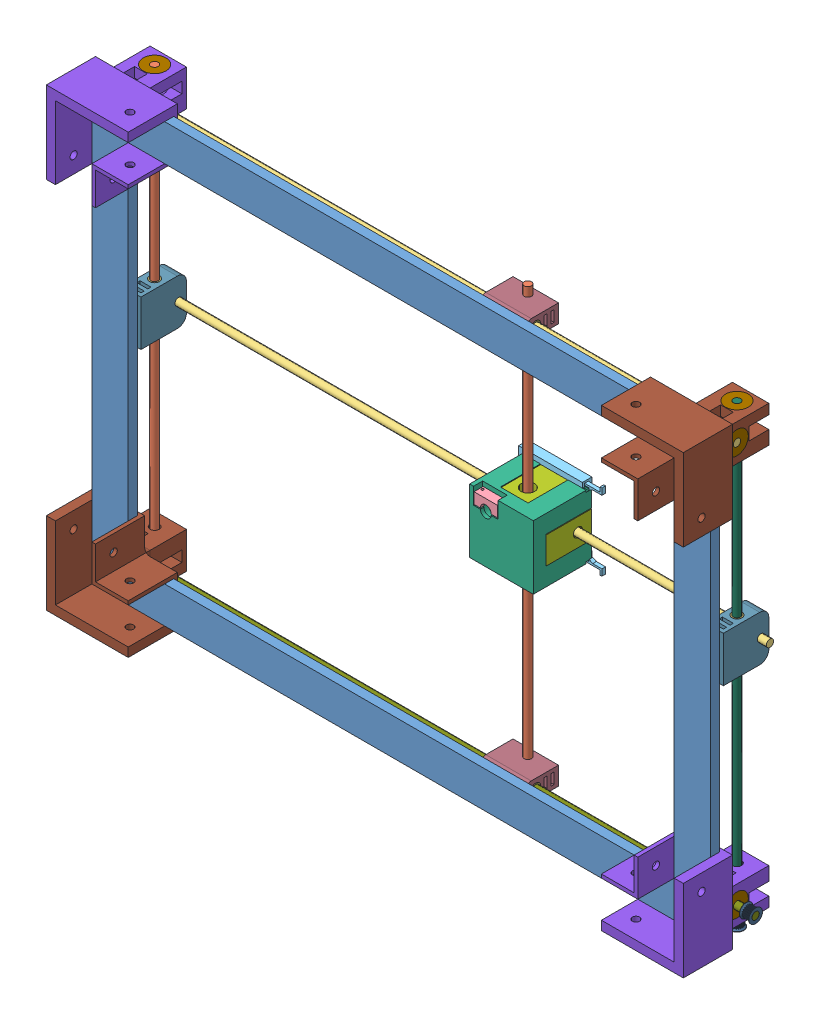
SolidWorks assembly Assemblage_XY, configuration Défaut. Lengths in mm.
Overall size (711.84 510.5 125.29).
50 component instances, 16 part files, 70 mates.
Components (placement in the parent):
- Cadre_XY-1: Cadre_XY [Défaut] at (379.0068 -247.2078 675) size (680 480 10)
- AXE_8X480-2: AXE_8X480 [Défaut] at (-280.9932 -247.2078 636) x (0.987721 0 0.156231) z (0 1 0) size (8 8 480)
- AXE_8X680-1: AXE_8X680 [Défaut] at (379.0068 212.7922 656) x (0 0.013067 0.999915) z (-1 0 0) size (8 8 680)
- AXE_8X480-3: AXE_8X480 [Défaut] at (132.8746 232.7922 639.7) x (0.999527 0 0.030742) z (0 -1 0) size (8 8 480)
- AXE_8X680-3: AXE_8X680 [Défaut] at (-300.9932 3.8544 619.7) x (0 -0.696158 -0.717888) z (1 0 0) size (8 8 680)
- P3DMIPC-Tête_complete-1: P3DMIPC-Tête_complete [Défaut] at (88.682 17.2244 635.2981) x (0 1 0) z (1 0 0) size (84 69 89)
  - P3DMIPC-Clip_Buse_E3D-1: P3DMIPC-Clip_Buse_E3D [Défaut] at (17.0518 23.4109 40.0035) x (1 0 0) z (0 1 0) size (12 26 10)
  - P3DMIPC-Clip_tête-1: P3DMIPC-Clip_tête [Défaut] at (26.9018 -25.0891 4.5597) x (1 0 0) z (0 -1 0) size (84 89 10.5)
  - P3DMIPC-Porte_Buse_E3DX1-1: P3DMIPC-Porte_Buse_E3DX1 [Défaut] at (22.03 33.4019 79.1927) x (0 0 1) z (0 -1 0) size (70 70 64)
  - P3DMIPC-Chariot-1: P3DMIPC-Chariot [Défaut] at (-48.37 -30.5981 79.1927) size (70 50 70)
- Angle_magique_G-1: Angle_magique_G [Défaut] at (379.0068 -247.2078 675) x (-1 0 0) z (0 0 -1) size (91.34 90 104)
- F608ZZ-1: F608ZZ [Défaut] at (372.0068 -227.2078 656) x (0 -0.924225 -0.381849) z (1 0 0) size (25 25 7)
- Angle_magique_G-4: Angle_magique_G [Défaut] at (-300.9932 232.7922 675) x (1 0 0) z (0 0 -1) size (91.34 90 104)
- pulley_gt2_3mm_20t-10: pulley_gt2_3mm_20t [Défaut] at (-280.9932 209.5422 636) x (0.106795 0 0.994281) z (0 1 0) size (15 15 10.5)
- pulley_gt2_3mm_20t-11: pulley_gt2_3mm_20t [Défaut] at (-277.7432 212.7922 656) x (0 0.106795 0.994281) z (-1 0 0) size (15 15 10.5)
- pulley_gt2_3mm_20t-12: pulley_gt2_3mm_20t [Défaut] at (-280.9932 -236.4578 636) x (-0.771074 0 0.636745) z (0 1 0) size (15 15 10.5)
- pulley_gt2_3mm_20t-13: pulley_gt2_3mm_20t [Défaut] at (-277.7432 -227.2078 656) x (0 0.106795 0.994281) z (-1 0 0) size (15 15 10.5)
- pulley_gt2_3mm_20t-15: pulley_gt2_3mm_20t [Défaut] at (359.0068 222.0422 636) x (-0.106795 0 0.994281) z (0 -1 0) size (15 15 10.5)
- pulley_gt2_3mm_20t-16: pulley_gt2_3mm_20t [Défaut] at (368.2568 212.7922 656) x (0 0.106795 0.994281) z (-1 0 0) size (15 15 10.5)
- F608ZZ-2: F608ZZ [Défaut] at (-280.9932 225.7922 636) x (-0.546944 0 0.837169) z (0 1 0) size (25 25 7)
- F608ZZ-3: F608ZZ [Défaut] at (-293.9932 212.7922 656) x (0 0 1) z (-1 0 0) size (25 25 7)
- F608ZZ-4: F608ZZ [Défaut] at (-293.9932 -227.2078 656) x (0 0 1) z (-1 0 0) size (25 25 7)
- F608ZZ-5: F608ZZ [Défaut] at (-280.9932 -240.2078 636) x (-0.924225 0 -0.381849) z (0 -1 0) size (25 25 7)
- F608ZZ-6: F608ZZ [Défaut] at (359.0068 -240.2078 636) x (-0.546944 0 0.837169) z (0 -1 0) size (25 25 7)
- F608ZZ-7: F608ZZ [Défaut] at (372.0068 212.7922 656) x (0 0 1) z (1 0 0) size (25 25 7)
- F608ZZ-8: F608ZZ [Défaut] at (359.0068 225.7922 636) x (0 0 1) z (0 1 0) size (25 25 7)
- Angle_magique_D-1: Angle_magique_D [Défaut] at (-300.9932 -247.2078 675) x (0 1 0) z (0 0 -1) size (90 91.34 104)
- Angle_magique_D-2: Angle_magique_D [Défaut] at (379.0068 232.7922 675) x (0 -1 0) z (0 0 -1) size (90 91.34 104)
- Assemblage_glissière_block_belt_palier_AR-1: Assemblage_glissière_block_belt_palier_AR [Défaut] at (253.3996 -186.4667 609.4689) x (0 -1 0) z (-1 0 0) size (20 35 50)
  - ultimaker_cuivre_fritté_douille_8mmx11mmx22 mm-1: ultimaker_cuivre_fritté_douille_8mmx11mmx22 mm [Défaut] at (40.7411 46.5311 95.5249) size (11 11 22)
  - ultimaker_cuivre_fritté_douille_8mmx11mmx22 mm-2: ultimaker_cuivre_fritté_douille_8mmx11mmx22 mm [Défaut] at (40.7411 46.5311 123.5249) size (11 11 22)
  - Glisière_block_belt_AR-2: Glisière_block_belt_AR [Défaut] at (50.7411 14.5311 95.5249) size (20 35 50)
- Assemblage_glissière_block_belt_palier_AR-2: Assemblage_glissière_block_belt_palier_AR [Défaut] at (12.3497 172.0511 609.4689) x (0 1 0) z (1 0 0) size (20 35 50)
  - ultimaker_cuivre_fritté_douille_8mmx11mmx22 mm-1: ultimaker_cuivre_fritté_douille_8mmx11mmx22 mm [Défaut] at (40.7411 46.5311 95.5249) size (11 11 22)
  - ultimaker_cuivre_fritté_douille_8mmx11mmx22 mm-2: ultimaker_cuivre_fritté_douille_8mmx11mmx22 mm [Défaut] at (40.7411 46.5311 123.5249) size (11 11 22)
  - Glisière_block_belt_AR-2: Glisière_block_belt_AR [Défaut] at (50.7411 14.5311 95.5249) size (20 35 50)
- pulley_gt2_3mm_20t-17: pulley_gt2_3mm_20t [Défaut] at (368.2568 -227.2078 656) x (0 0.106795 0.994281) z (-1 0 0) size (15 15 10.5)
- pulley_gt2_3mm_20t-18: pulley_gt2_3mm_20t [Défaut] at (359.0068 -223.9578 636) x (0.203502 0 0.979074) z (0 -1 0) size (15 15 10.5)
- Assemblage_glissière_block_belt_palier_GD-1: Assemblage_glissière_block_belt_palier_GD [Défaut] at (364.4936 -71.1456 631.6132) x (-1 0 0) z (0 1 0) size (20 50 50)
  - Glisière_block_belt_GD-1: Glisière_block_belt_GD [Défaut] at (15.4869 -20.6132 50) size (20 50 50)
  - ultimaker_cuivre_fritté_douille_8mmx11mmx22 mm-1: ultimaker_cuivre_fritté_douille_8mmx11mmx22 mm [Défaut] at (5.4869 4.3868 50) size (11 11 22)
  - ultimaker_cuivre_fritté_douille_8mmx11mmx22 mm-2: ultimaker_cuivre_fritté_douille_8mmx11mmx22 mm [Défaut] at (5.4869 4.3868 78) size (11 11 22)
- Assemblage_glissière_block_belt_palier_GD-2: Assemblage_glissière_block_belt_palier_GD [Défaut] at (-286.4801 78.8544 631.6132) x (1 0 0) z (0 -1 0) size (20 50 50)
  - Glisière_block_belt_GD-1: Glisière_block_belt_GD [Défaut] at (15.4869 -20.6132 50) size (20 50 50)
  - ultimaker_cuivre_fritté_douille_8mmx11mmx22 mm-1: ultimaker_cuivre_fritté_douille_8mmx11mmx22 mm [Défaut] at (5.4869 4.3868 50) size (11 11 22)
  - ultimaker_cuivre_fritté_douille_8mmx11mmx22 mm-2: ultimaker_cuivre_fritté_douille_8mmx11mmx22 mm [Défaut] at (5.4869 4.3868 78) size (11 11 22)
- AXE_8X500_Moteur-1: AXE_8X500_Moteur [Défaut] at (359.0068 -267.7078 636) x (0.283264 0 -0.959042) z (0 1 0) size (8 8 500.5)
- AXE_8X700_Moteur-1: AXE_8X700_Moteur [Défaut] at (399.5068 -227.2078 656) x (0 0 1) z (-1 0 0) size (8 8 700.5)
- pulley_gt2_3mm_20t-19: pulley_gt2_3mm_20t [Défaut] at (359.0068 -256.2078 636) x (0.203502 0 0.979074) z (0 -1 0) size (15 15 10.5)
- pulley_gt2_3mm_20t-20: pulley_gt2_3mm_20t [Défaut] at (388.0068 -227.2078 656) x (0 0.203502 0.979074) z (1 0 0) size (15 15 10.5)
Mates (geometry in assembly coordinates):
- Coaxiale1: concentric anti-aligned: cylinder of AXE_8X680-3 through (379.0068 3.8544 619.7) axis (-1 0 0) radius 4; cylinder of P3DMIPC-Tête_complete-1/P3DMIPC-Chariot-1 through (163.8746 3.8544 619.7) axis (1 0 0) radius 5
- Coaxiale2: concentric anti-aligned: cylinder of AXE_8X480-3 through (132.8746 -247.2078 639.7) axis (0 1 0) radius 4; cylinder of P3DMIPC-Tête_complete-1/P3DMIPC-Chariot-1 through (132.8746 -27.1456 639.7) axis (0 -1 0) radius 5
- Coïncidente14: coincident anti-aligned: plane of Cadre_XY-1 through (379.0068 -247.2078 675) normal (0 0 -1); plane of Angle_magique_G-1 through (379.0068 -247.2078 675) normal (0 0 1)
- Coïncidente15: coincident anti-aligned: plane of Cadre_XY-1 through (379.0068 -247.2078 685) normal (1 0 0); plane of Angle_magique_G-1 through (379.0068 -247.2078 725) normal (-1 0 0)
- Coïncidente16: coincident anti-aligned: plane of Cadre_XY-1 through (379.0068 -247.2078 685) normal (0 -1 0); plane of Angle_magique_G-1 through (299.0068 -247.2078 725) normal (0 1 0)
- Coïncidente27: coincident anti-aligned: plane of Cadre_XY-1 through (379.0068 -247.2078 675) normal (0 0 -1); plane of Angle_magique_G-4 through (-300.9932 232.7922 675) normal (0 0 1)
- Coïncidente28: coincident anti-aligned: plane of Cadre_XY-1 through (379.0068 232.7922 685) normal (0 1 0); plane of Angle_magique_G-4 through (-220.9932 232.7922 725) normal (0 -1 0)
- Coïncidente29: coincident anti-aligned: plane of Cadre_XY-1 through (-300.9932 -247.2078 685) normal (-1 0 0); plane of Angle_magique_G-4 through (-300.9932 232.7922 725) normal (1 0 0)
- Coaxiale17: concentric anti-aligned: cylinder of AXE_8X680-1 through (-300.9932 212.7922 656) axis (1 0 0) radius 4; cylinder of pulley_gt2_3mm_20t-11 through (-277.7432 212.7922 656) axis (-1 0 0) radius 4
- Coaxiale18: concentric aligned: cylinder of AXE_8X680-1 through (-300.9932 212.7922 656) axis (1 0 0) radius 4; cylinder of Angle_magique_G-4 through (-310.9932 212.7922 656) axis (1 0 0) radius 5
- Coïncidente30: coincident aligned: plane of Cadre_XY-1 through (-300.9932 -247.2078 685) normal (-1 0 0); plane of AXE_8X680-1 through (-300.9932 212.7922 656) normal (-1 0 0)
- Distance2: distance = 2.75 mm anti-aligned: plane of pulley_gt2_3mm_20t-11 through (-278.7432 212.7922 656) normal (1 0 0); plane of Angle_magique_G-4 through (-275.9932 192.7922 621) normal (-1 0 0)
- Coaxiale19: concentric anti-aligned: cylinder of AXE_8X680-1 through (-300.9932 212.7922 656) axis (1 0 0) radius 4; cylinder of pulley_gt2_3mm_20t-16 through (368.2568 212.7922 656) axis (-1 0 0) radius 4
- Coaxiale24: concentric aligned: cylinder of AXE_8X480-2 through (-280.9932 232.7922 636) axis (0 -1 0) radius 4; cylinder of Angle_magique_G-4 through (-280.9932 232.7923 636) axis (0 -1 0) radius 5
- Coaxiale25: concentric anti-aligned: cylinder of AXE_8X480-2 through (-280.9932 232.7922 636) axis (0 -1 0) radius 4; cylinder of pulley_gt2_3mm_20t-10 through (-280.9932 209.5422 636) axis (0 1 0) radius 4
- Coïncidente34: coincident aligned: plane of Cadre_XY-1 through (379.0068 232.7922 685) normal (0 1 0); plane of AXE_8X480-2 through (-280.9932 232.7922 636) normal (0 1 0)
- Distance4: distance = 2.75 mm anti-aligned: plane of pulley_gt2_3mm_20t-10 through (-280.9932 210.5422 636) normal (0 -1 0); plane of Angle_magique_G-4 through (-275.9932 207.7922 621) normal (0 1 0)
- Coaxiale26: concentric anti-aligned: cylinder of AXE_8X480-2 through (-280.9932 232.7922 636) axis (0 -1 0) radius 4; cylinder of pulley_gt2_3mm_20t-12 through (-280.9932 -236.4578 636) axis (0 1 0) radius 4
- Coïncidente44: coincident anti-aligned: plane of Cadre_XY-1 through (379.0068 -247.2078 675) normal (0 0 -1); plane of Angle_magique_D-1 through (-300.9932 -247.2078 675) normal (0 0 1)
- Coïncidente45: coincident anti-aligned: plane of Cadre_XY-1 through (379.0068 -247.2078 685) normal (0 -1 0); plane of Angle_magique_D-1 through (-300.9932 -247.2078 725) normal (0 1 0)
- Coïncidente46: coincident anti-aligned: plane of Cadre_XY-1 through (-300.9932 -247.2078 685) normal (-1 0 0); plane of Angle_magique_D-1 through (-300.9932 -167.2078 725) normal (1 0 0)
- Distance10: distance = 2.75 mm anti-aligned: plane of Angle_magique_D-1 through (-260.9932 -222.2078 621) normal (0 -1 0); plane of pulley_gt2_3mm_20t-12 through (-280.9932 -224.9578 636) normal (0 1 0)
- Coïncidente51: coincident anti-aligned: plane of Cadre_XY-1 through (379.0068 -247.2078 675) normal (0 0 -1); plane of Angle_magique_D-2 through (379.0068 232.7922 675) normal (0 0 1)
- Coïncidente52: coincident anti-aligned: plane of Cadre_XY-1 through (379.0068 232.7922 685) normal (0 1 0); plane of Angle_magique_D-2 through (379.0068 232.7922 725) normal (0 -1 0)
- Coïncidente53: coincident anti-aligned: plane of Cadre_XY-1 through (379.0068 -247.2078 685) normal (1 0 0); plane of Angle_magique_D-2 through (379.0068 152.7922 725) normal (-1 0 0)
- Distance11: distance = 2.75 mm anti-aligned: plane of pulley_gt2_3mm_20t-15 through (359.0068 210.5422 636) normal (0 -1 0); plane of Angle_magique_D-2 through (339.0068 207.7922 621) normal (0 1 0)
- Distance12: distance = 2.75 mm anti-aligned: plane of Angle_magique_D-2 through (354.0068 207.7922 621) normal (1 0 0); plane of pulley_gt2_3mm_20t-16 through (356.7568 212.7922 656) normal (-1 0 0)
- Coaxiale39: concentric anti-aligned: cylinder of AXE_8X680-1 through (-300.9932 212.7922 656) axis (1 0 0) radius 4; cylinder of Assemblage_glissière_block_belt_palier_AR-2/ultimaker_cuivre_fritté_douille_8mmx11mmx22 mm-1 through (129.8746 212.7922 656) axis (-1 0 0) radius 4
- Coaxiale42: concentric anti-aligned: cylinder of AXE_8X480-3 through (132.8746 -247.2078 639.7) axis (0 1 0) radius 4; cylinder of Assemblage_glissière_block_belt_palier_AR-2/Glisière_block_belt_AR-2 through (132.8746 222.7922 639.7) axis (0 -1 0) radius 4
- Coaxiale43: concentric aligned: cylinder of AXE_8X480-3 through (132.8746 -247.2078 639.7) axis (0 1 0) radius 4; cylinder of Assemblage_glissière_block_belt_palier_AR-1/Glisière_block_belt_AR-2 through (132.8746 -237.2078 639.7) axis (0 1 0) radius 4
- Coaxiale50: concentric anti-aligned: cylinder of F608ZZ-7 through (377.5068 212.7922 656) axis (-1 0 0) radius 11; cylinder of Angle_magique_D-2 through (372.0068 212.7922 656) axis (1 0 0) radius 11
- Coïncidente63: coincident anti-aligned: plane of F608ZZ-7 through (372.0068 212.7922 656) normal (-1 0 0); plane of Angle_magique_D-2 through (372.0068 212.7922 656) normal (1 0 0)
- Coaxiale51: concentric anti-aligned: cylinder of F608ZZ-8 through (359.0068 231.2922 636) axis (0 -1 0) radius 11; cylinder of Angle_magique_D-2 through (359.0068 225.7922 636) axis (0 1 0) radius 11
- Coïncidente64: coincident anti-aligned: plane of F608ZZ-8 through (359.0068 225.7922 636) normal (0 -1 0); plane of Angle_magique_D-2 through (359.0068 225.7922 636) normal (0 1 0)
- Coïncidente65: coincident anti-aligned: plane of Angle_magique_G-4 through (-280.9932 225.7922 636) normal (0 1 0); plane of F608ZZ-2 through (-280.9932 225.7922 636) normal (0 -1 0)
- Coaxiale53: concentric anti-aligned: cylinder of Angle_magique_G-4 through (-280.9932 225.7922 636) axis (0 1 0) radius 11; cylinder of F608ZZ-2 through (-280.9932 231.2922 636) axis (0 -1 0) radius 11
- Coaxiale54: concentric anti-aligned: cylinder of Angle_magique_G-4 through (-293.9932 212.7922 656) axis (-1 0 0) radius 11; cylinder of F608ZZ-3 through (-299.4932 212.7922 656) axis (1 0 0) radius 11
- Coïncidente66: coincident anti-aligned: plane of Angle_magique_G-4 through (-293.9932 212.7922 656) normal (-1 0 0); plane of F608ZZ-3 through (-293.9932 212.7922 656) normal (1 0 0)
- Coaxiale57: concentric anti-aligned: cylinder of F608ZZ-4 through (-299.4932 -227.2078 656) axis (1 0 0) radius 11; cylinder of Angle_magique_D-1 through (-293.9932 -227.2078 656) axis (-1 0 0) radius 11
- Coïncidente69: coincident anti-aligned: plane of F608ZZ-4 through (-293.9932 -227.2078 656) normal (1 0 0); plane of Angle_magique_D-1 through (-293.9932 -227.2078 656) normal (-1 0 0)
- Coïncidente70: coincident anti-aligned: plane of F608ZZ-5 through (-280.9932 -240.2078 636) normal (0 1 0); plane of Angle_magique_D-1 through (-280.9932 -240.2078 636) normal (0 -1 0)
- Coaxiale58: concentric anti-aligned: cylinder of F608ZZ-5 through (-280.9932 -245.7078 636) axis (0 1 0) radius 11; cylinder of Angle_magique_D-1 through (-280.9932 -240.2078 636) axis (0 -1 0) radius 11
- Distance14: distance = 2.75 mm anti-aligned: plane of Angle_magique_G-1 through (354.0068 -222.2078 621) normal (0 -1 0); plane of pulley_gt2_3mm_20t-18 through (359.0068 -224.9578 636) normal (0 1 0)
- Distance15: distance = 2.75 mm anti-aligned: plane of Angle_magique_G-1 through (354.0068 -207.2078 621) normal (1 0 0); plane of pulley_gt2_3mm_20t-17 through (356.7568 -227.2078 656) normal (-1 0 0)
- Coïncidente73: coincident anti-aligned: plane of Angle_magique_G-1 through (359.0068 -240.2078 636) normal (0 -1 0); plane of F608ZZ-6 through (359.0068 -240.2078 636) normal (0 1 0)
- Coaxiale61: concentric anti-aligned: cylinder of Angle_magique_G-1 through (359.0068 -240.2078 636) axis (0 -1 0) radius 11; cylinder of F608ZZ-6 through (359.0068 -245.7078 636) axis (0 1 0) radius 11
- Coïncidente74: coincident anti-aligned: plane of Angle_magique_G-1 through (372.0068 -227.2078 656) normal (1 0 0); plane of F608ZZ-1 through (372.0068 -227.2078 656) normal (-1 0 0)
- Coaxiale62: concentric anti-aligned: cylinder of Angle_magique_G-1 through (372.0068 -227.2078 656) axis (1 0 0) radius 11; cylinder of F608ZZ-1 through (377.5068 -227.2078 656) axis (-1 0 0) radius 11
- Coaxiale64: concentric anti-aligned: cylinder of AXE_8X680-3 through (379.0068 3.8544 619.7) axis (-1 0 0) radius 4; cylinder of Assemblage_glissière_block_belt_palier_GD-1/Glisière_block_belt_GD-1 through (349.0068 3.8544 619.7) axis (1 0 0) radius 4
- Coaxiale65: concentric anti-aligned: cylinder of Assemblage_glissière_block_belt_palier_GD-2/ultimaker_cuivre_fritté_douille_8mmx11mmx22 mm-1 through (-280.9932 6.8544 636) axis (0 1 0) radius 4; cylinder of AXE_8X480-2 through (-280.9932 232.7922 636) axis (0 -1 0) radius 4
- Coaxiale66: concentric aligned: cylinder of AXE_8X680-3 through (379.0068 3.8544 619.7) axis (-1 0 0) radius 4; cylinder of Assemblage_glissière_block_belt_palier_GD-2/Glisière_block_belt_GD-1 through (-270.9932 3.8544 619.7) axis (-1 0 0) radius 4
- Coïncidente75: coincident aligned: plane of Cadre_XY-1 through (-300.9932 -247.2078 685) normal (-1 0 0); plane of AXE_8X680-3 through (-300.9932 3.8544 619.7) normal (-1 0 0)
- Coïncidente76: coincident aligned: plane of Cadre_XY-1 through (379.0068 -247.2078 685) normal (0 -1 0); plane of AXE_8X480-3 through (132.8746 -247.2078 639.7) normal (0 -1 0)
- Distance17: distance = 2.75 mm anti-aligned: plane of pulley_gt2_3mm_20t-13 through (-278.7432 -227.2078 656) normal (1 0 0); plane of Angle_magique_D-1 through (-275.9932 -222.2078 621) normal (-1 0 0)
- Coaxiale67: concentric anti-aligned: cylinder of Angle_magique_G-1 through (389.0068 -227.2078 656) axis (-1 0 0) radius 5; cylinder of AXE_8X700_Moteur-1 through (-300.9932 -227.2078 656) axis (1 0 0) radius 4
- Coaxiale68: concentric aligned: cylinder of Assemblage_glissière_block_belt_palier_AR-1/ultimaker_cuivre_fritté_douille_8mmx11mmx22 mm-2 through (107.8746 -227.2078 656) axis (1 0 0) radius 4; cylinder of AXE_8X700_Moteur-1 through (-300.9932 -227.2078 656) axis (1 0 0) radius 4
- Coaxiale69: concentric aligned: cylinder of Angle_magique_D-1 through (-310.9932 -227.2078 656) axis (1 0 0) radius 5; cylinder of AXE_8X700_Moteur-1 through (-300.9932 -227.2078 656) axis (1 0 0) radius 4
- Coïncidente80: coincident aligned: plane of Cadre_XY-1 through (-300.9932 -247.2078 685) normal (-1 0 0); plane of AXE_8X700_Moteur-1 through (-300.9932 -227.2078 656) normal (-1 0 0)
- Coaxiale70: concentric anti-aligned: cylinder of pulley_gt2_3mm_20t-13 through (-277.7432 -227.2078 656) axis (-1 0 0) radius 4; cylinder of AXE_8X700_Moteur-1 through (-300.9932 -227.2078 656) axis (1 0 0) radius 4
- Coaxiale71: concentric anti-aligned: cylinder of pulley_gt2_3mm_20t-17 through (368.2568 -227.2078 656) axis (-1 0 0) radius 4; cylinder of AXE_8X700_Moteur-1 through (-300.9932 -227.2078 656) axis (1 0 0) radius 4
- Coaxiale72: concentric aligned: cylinder of Assemblage_glissière_block_belt_palier_GD-1/ultimaker_cuivre_fritté_douille_8mmx11mmx22 mm-2 through (359.0068 28.8544 636) axis (0 -1 0) radius 4; cylinder of AXE_8X500_Moteur-1 through (359.0068 232.7922 636) axis (0 -1 0) radius 4
- Coaxiale73: concentric anti-aligned: cylinder of Angle_magique_G-1 through (359.0068 -247.2078 636) axis (0 1 0) radius 5; cylinder of AXE_8X500_Moteur-1 through (359.0068 232.7922 636) axis (0 -1 0) radius 4
- Coaxiale74: concentric aligned: cylinder of Angle_magique_D-2 through (359.0068 242.7922 636) axis (0 -1 0) radius 5; cylinder of AXE_8X500_Moteur-1 through (359.0068 232.7922 636) axis (0 -1 0) radius 4
- Coaxiale75: concentric aligned: cylinder of pulley_gt2_3mm_20t-15 through (359.0068 222.0422 636) axis (0 -1 0) radius 4; cylinder of AXE_8X500_Moteur-1 through (359.0068 232.7922 636) axis (0 -1 0) radius 4
- Coaxiale76: concentric aligned: cylinder of pulley_gt2_3mm_20t-18 through (359.0068 -223.9578 636) axis (0 -1 0) radius 4; cylinder of AXE_8X500_Moteur-1 through (359.0068 232.7922 636) axis (0 -1 0) radius 4
- Coïncidente81: coincident aligned: plane of Cadre_XY-1 through (379.0068 232.7922 685) normal (0 1 0); plane of AXE_8X500_Moteur-1 through (359.0068 232.7922 636) normal (0 1 0)
- Coaxiale77: concentric aligned: cylinder of AXE_8X500_Moteur-1 through (359.0068 232.7922 636) axis (0 -1 0) radius 4; cylinder of pulley_gt2_3mm_20t-19 through (359.0068 -256.2078 636) axis (0 -1 0) radius 4
- Coïncidente82: coincident aligned: plane of AXE_8X500_Moteur-1 through (359.0068 -267.7078 636) normal (0 -1 0); plane of pulley_gt2_3mm_20t-19 through (359.0068 -267.7078 636) normal (0 -1 0)
- Coïncidente83: coincident aligned: plane of AXE_8X700_Moteur-1 through (399.5068 -227.2078 656) normal (1 0 0); plane of pulley_gt2_3mm_20t-20 through (399.5068 -227.2078 656) normal (1 0 0)
- Coaxiale78: concentric aligned: cylinder of AXE_8X700_Moteur-1 through (-300.9932 -227.2078 656) axis (1 0 0) radius 4; cylinder of pulley_gt2_3mm_20t-20 through (388.0068 -227.2078 656) axis (1 0 0) radius 4
